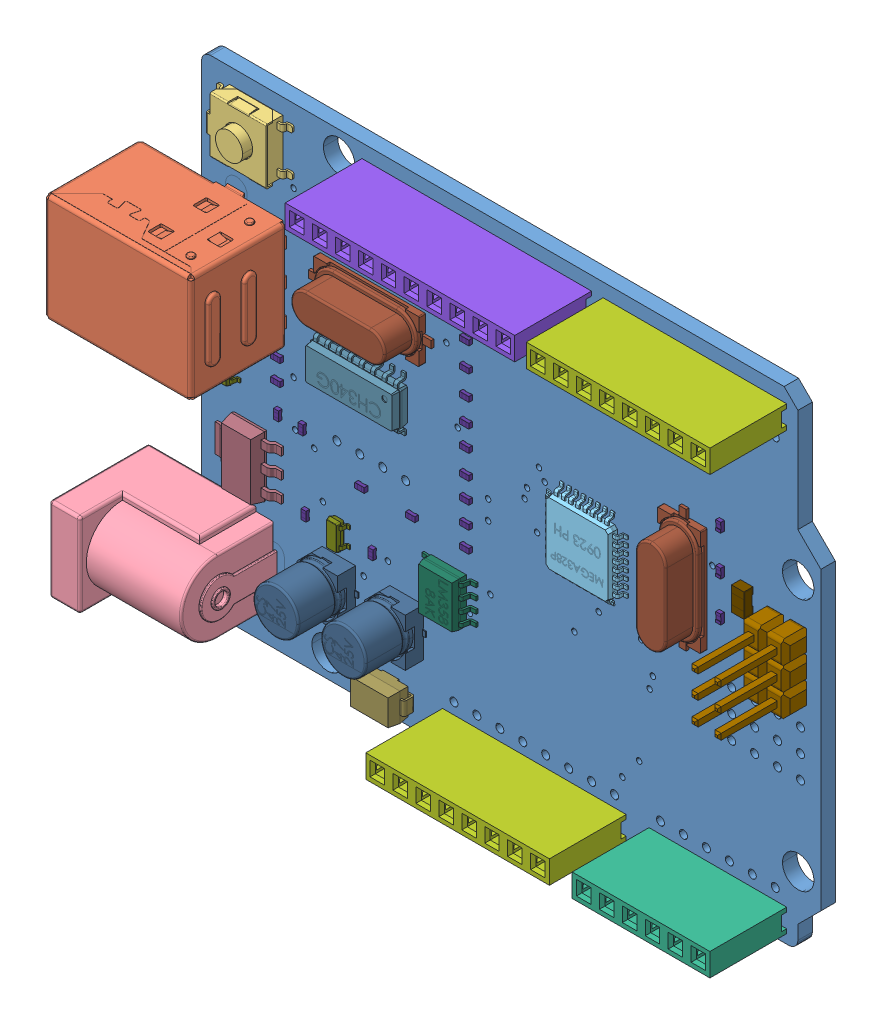
SolidWorks assembly Assembly Arduino Uno R3, configuration Default. Lengths in mm.
Overall size (75 53.3 16.1).
46 component instances, 18 part files, 0 mates.
Components (placement in the parent):
- Assembly Arduino Uno R3.STEP-1: Assembly Arduino Uno R3.STEP [Default] at origin size (75 53.3 16.1)
  - 1. Arduino uno PCB.STEP-1: 1. Arduino uno PCB.STEP [Default] at (23.1768 3.2644 56.3804) size (68.53 53.3 1.6)
  - 2. USB.STEP-1: 2. USB.STEP [Default] at (-0.091 39.0544 63.5804) x (0 -1 0) z (-1 0 0) size (14.95 14.22 16.6)
  - 12. Button arduino.STEP-1: 12. Button arduino.STEP [Default] at (-16.3125 58.8663 57.9804) size (8.4 6.2 3)
  - 3. dc jack arduino.STEP-1: 3. dc jack arduino.STEP [Default] at (-15.671 11.3644 63.4804) x (0 1 0) z (1 0 0) size (9.8 16.1 14.4)
  - 4. atmega 328p.STEP-1: 4. atmega 328p.STEP [Default] at (32.929 30.6944 58.7304) x (-1 0 0) z (0 0 -1) size (8.99 8.99 1.2)
  - 2.0  header female 6.STEP-1: 2.0  header female 6.STEP [Default] at (52.3937 64.9176 37.8614) x (0 1 0) z (1 0 0) size (2.54 11.7 15.24)
  - 2.0  header female 8.STEP-1: 2.0  header female 8.STEP [Default] at (34.6337 64.9176 37.8614) x (0 1 0) z (1 0 0) size (2.54 11.7 20.32)
  - 2.0  header female 10.STEP-1: 2.0  header female 10.STEP [Default] at (30.799 113.1576 37.8614) x (0 1 0) z (1 0 0) size (2.54 11.7 25.4)
  - 2.0  header female 8.STEP-2: 2.0  header female 8.STEP [Default] at (52.3946 113.1576 37.8614) x (0 1 0) z (1 0 0) size (2.54 11.7 20.32)
  - 5. header male.STEP-1: 5. header male.STEP [Default] at (56.3437 33.5885 57.9804) x (0 1 0) z (0 0 1) size (7.62 5.08 12.7)
  - 10. cap arduino.STEP-1: 10. cap arduino.STEP [Default] at (12.0737 13.0344 59.9804) x (-1 0 0) z (0 0 -1) size (6 5.3 6.2)
  - 10. cap arduino.STEP-2: 10. cap arduino.STEP [Default] at (4.579 13.0344 59.9804) x (-1 0 0) z (0 0 -1) size (6 5.3 6.2)
  - 8. Arduino part 16MHZ.STEP-1: 8. Arduino part 16MHZ.STEP [Default] at (14.849 43.7344 57.9804) size (13.58 4.8 3.85)
  - 8. Arduino part 16MHZ.STEP-2: 8. Arduino part 16MHZ.STEP [Default] at (41.3137 38.6244 57.9804) x (0 1 0) z (0 0 1) size (13.58 4.8 3.85)
  - 6. diode.STEP-1: 6. diode.STEP [Default] at (11.139 5.7644 59.1804) x (0 1 0) z (0 0 1) size (3.11 5.3 2.43)
  - 13. LM1117.STEP-1: 13. LM1117.STEP [Default] at (-16.299 58.867 57.8807) size (7.32 6.7 1.7)
  - 14. Micro chip part Arduino.STEP-1: 14. Micro chip part Arduino.STEP [Default] at (-16.306 58.8741 57.9804) size (9.9 6 1.75)
  - 7.Lm358 arduino.STEP-1: 7.Lm358 arduino.STEP [Default] at (17.789 18.7444 58.8704) size (6 4.9 1.75)
  - 11. Transistor.STEP-1: 11. Transistor.STEP [Default] at (-16.3121 58.8727 57.9804) size (2.34 2.92 1)
  - 11. Transistor.STEP-2: 11. Transistor.STEP [Default] at (-4.1821 48.9727 57.9804) size (2.34 2.92 1)
  - 9. part.STEP-1: 9. part.STEP [Default] at (19.109 45.7244 58.3804) x (1 0 0) z (0 1 0) size (1.05 0.4 0.55)
  - 9. part.STEP-2: 9. part.STEP [Default] at (19.109 43.3944 58.3804) x (1 0 0) z (0 1 0) size (1.05 0.4 0.55)
  - 9. part.STEP-3: 9. part.STEP [Default] at (19.109 40.6944 58.3804) x (1 0 0) z (0 1 0) size (1.05 0.4 0.55)
  - 9. part.STEP-4: 9. part.STEP [Default] at (19.109 37.9944 58.3804) x (1 0 0) z (0 1 0) size (1.05 0.4 0.55)
  - 9. part.STEP-5: 9. part.STEP [Default] at (19.109 33.0944 58.3804) x (1 0 0) z (0 1 0) size (1.05 0.4 0.55)
  - 9. part.STEP-6: 9. part.STEP [Default] at (19.109 35.4244 58.3804) x (1 0 0) z (0 1 0) size (1.05 0.4 0.55)
  - 9. part.STEP-7: 9. part.STEP [Default] at (19.109 30.4244 58.3804) x (1 0 0) z (0 1 0) size (1.05 0.4 0.55)
  - 9. part.STEP-8: 9. part.STEP [Default] at (19.109 28.1244 58.3804) x (1 0 0) z (0 1 0) size (1.05 0.4 0.55)
  - 9. part.STEP-9: 9. part.STEP [Default] at (19.109 25.7244 58.3804) x (1 0 0) z (0 1 0) size (1.05 0.4 0.55)
  - 9. part.STEP-10: 9. part.STEP [Default] at (19.109 23.4244 58.3804) x (1 0 0) z (0 1 0) size (1.05 0.4 0.55)
  - 15. part 1.STEP-1: 15. part 1.STEP [Default] at (49.8188 35.6465 58.9804) x (0 -1 0) z (1 0 0) size (2.62 1 1.38)
  - 9. part.STEP-11: 9. part.STEP [Default] at (48.0248 40.4298 57.9804) x (0 -1 0) z (-1 0 0) size (1.05 0.4 0.55)
  - 9. part.STEP-12: 9. part.STEP [Default] at (48.0248 36.0298 57.9804) x (0 -1 0) z (-1 0 0) size (1.05 0.4 0.55)
  - 9. part.STEP-13: 9. part.STEP [Default] at (48.0248 31.6298 57.9804) x (0 -1 0) z (-1 0 0) size (1.05 0.4 0.55)
  - 9. part.STEP-14: 9. part.STEP [Default] at (4.3842 45.5109 58.3804) x (1 0 0) z (0 1 0) size (1.05 0.4 0.55)
  - 9. part.STEP-15: 9. part.STEP [Default] at (8.4842 45.5109 58.3804) x (1 0 0) z (0 1 0) size (1.05 0.4 0.55)
  - 9. part.STEP-16: 9. part.STEP [Default] at (12.5842 45.5109 58.3804) x (1 0 0) z (0 1 0) size (1.05 0.4 0.55)
  - 9. part.STEP-17: 9. part.STEP [Default] at (-1.7801 31.2518 58.3804) x (1 0 0) z (0 1 0) size (1.05 0.4 0.55)
  - 9. part.STEP-18: 9. part.STEP [Default] at (-1.7801 28.9518 58.3804) x (1 0 0) z (0 1 0) size (1.05 0.4 0.55)
  - 9. part.STEP-19: 9. part.STEP [Default] at (7.5312 23.47 58.3804) x (1 0 0) z (0 1 0) size (1.05 0.4 0.55)
  - 9. part.STEP-20: 9. part.STEP [Default] at (13.1312 23.47 58.3804) x (1 0 0) z (0 1 0) size (1.05 0.4 0.55)
  - 9. part.STEP-21: 9. part.STEP [Default] at (-0.9044 25.5823 58.3804) x (0 1 0) z (-1 0 0) size (1.05 0.4 0.55)
  - 9. part.STEP-22: 9. part.STEP [Default] at (1.7956 25.5823 58.3804) x (0 1 0) z (-1 0 0) size (1.05 0.4 0.55)
  - 9. part.STEP-23: 9. part.STEP [Default] at (2.1347 17.489 58.3804) x (0 1 0) z (-1 0 0) size (1.05 0.4 0.55)
  - 9. part.STEP-24: 9. part.STEP [Default] at (9.5347 17.489 58.3804) x (0 1 0) z (-1 0 0) size (1.05 0.4 0.55)
